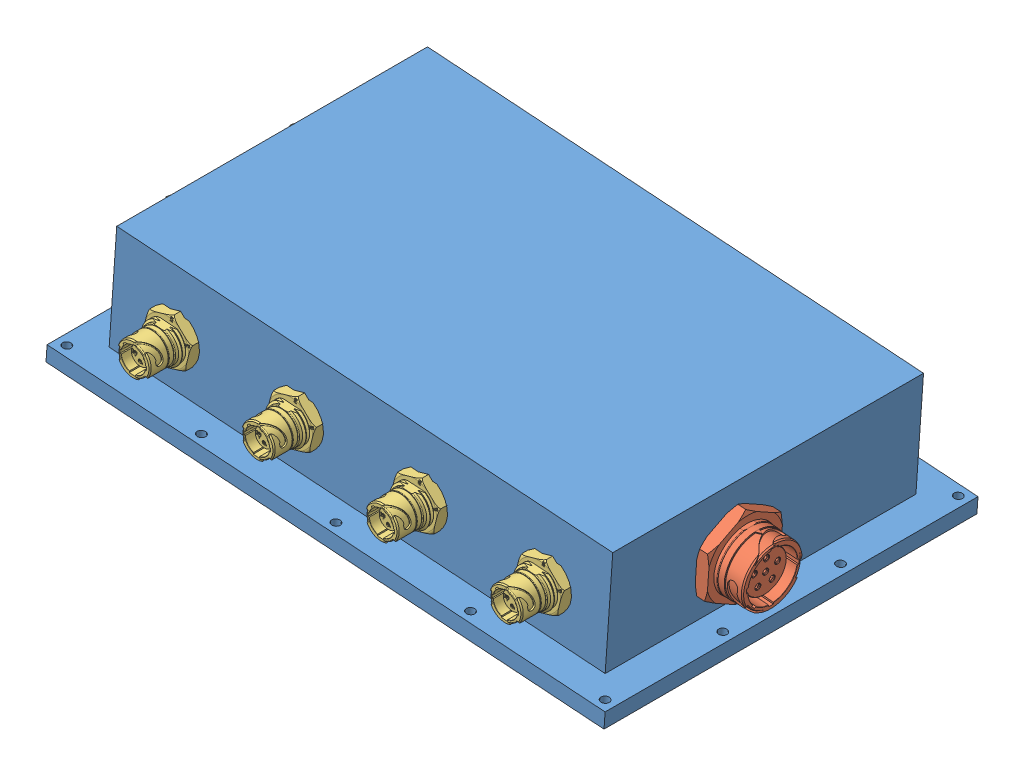
SolidWorks assembly PDB Lidless Assembly, configuration Default. Lengths in mm.
Overall size (238.42 66.62 160.89).
12 component instances, 3 part files, 33 mates.
Components (placement in the parent):
- Power Distribution Box & connector holes v1-1: Power Distribution Box & connector holes v1 [Default] at (68.8696 153.9223 199.977) x (-0.997564 0.069756 0) z (0 0 1) size (228.6 50.8 152.4)
- Samtec ACR 22-3: Samtec ACR 22 [Default] at (184.8303 120.3515 212.677) x (0 0 -1) z (0.997564 -0.069756 0) size (38.11 34.64 24.46)
- Samtec ACR-12 Plastic-2: Samtec ACR-12 Plastic [Default] at (-51.0387 136.8451 174.577) x (0 0 -1) z (-0.997564 0.069756 0) size (25.4 22 24.12)
- Samtec ACR-12 Plastic-13: Samtec ACR-12 Plastic [Default] at (92.436 126.8123 280.302) x (-0.997564 0.069756 0) z (0 0 1) size (25.4 22 24.12)
- Samtec ACR-12 Plastic-14: Samtec ACR-12 Plastic [Default] at (143.1122 123.2687 119.652) x (0.997564 -0.069756 0) z (0 0 -1) size (25.4 22 24.12)
- Samtec ACR-12 Plastic-15: Samtec ACR-12 Plastic [Default] at (143.1122 123.2687 280.302) x (-0.997564 0.069756 0) z (0 0 1) size (25.4 22 24.12)
- Samtec ACR-12 Plastic-16: Samtec ACR-12 Plastic [Default] at (41.7597 130.356 280.302) x (-0.997564 0.069756 0) z (0 0 1) size (25.4 22 24.12)
- Samtec ACR-12 Plastic-17: Samtec ACR-12 Plastic [Default] at (-8.9166 133.8996 280.302) x (-0.997564 0.069756 0) z (0 0 1) size (25.4 22 24.12)
- Samtec ACR-12 Plastic-18: Samtec ACR-12 Plastic [Default] at (-51.0387 136.8451 225.377) x (0 0 -1) z (-0.997564 0.069756 0) size (25.4 22 24.12)
- Samtec ACR-12 Plastic-19: Samtec ACR-12 Plastic [Default] at (92.436 126.8123 119.652) x (0.997564 -0.069756 0) z (0 0 -1) size (25.4 22 24.12)
- Samtec ACR-12 Plastic-20: Samtec ACR-12 Plastic [Default] at (41.7597 130.356 119.652) x (0.997564 -0.069756 0) z (0 0 -1) size (25.4 22 24.12)
- Samtec ACR-12 Plastic-21: Samtec ACR-12 Plastic [Default] at (-8.9166 133.8996 119.652) x (0.997564 -0.069756 0) z (0 0 -1) size (25.4 22 24.12)
Mates (geometry in assembly coordinates):
- Coincident50: coincident anti-aligned: plane of Power Distribution Box & connector holes v1-1 through (166.6785 96.1588 263.477) normal (0.997564 -0.069756 0); plane of Samtec ACR 22-3 through (168.4503 121.4969 212.677) normal (-0.997564 0.069756 0)
- Concentric32: concentric anti-aligned: circle of Power Distribution Box & connector holes v1-1; cylinder of Samtec ACR 22-3 through (184.8303 120.3515 212.677) axis (-0.997564 0.069756 0) radius 12.25
- Parallel30: parallel: line of Power Distribution Box & connector holes v1-1 through (167.1215 102.4933 136.477) axis (0.069756 0.997564 0); plane of Samtec ACR 22-3 through (167.8462 112.8577 197.677) normal (0 0 -1)
- Concentric35: concentric anti-aligned: cylinder of Power Distribution Box & connector holes v1-1 through (181.1204 120.6109 174.577) axis (-0.997564 0.069756 0) radius 10.2489; cylinder of Samtec ACR-12 Plastic-2 through (-51.0387 136.8451 174.577) axis (0.997564 -0.069756 0) radius 6.75
- Parallel59: parallel anti-aligned: plane of Power Distribution Box & connector holes v1-1 through (181.7299 129.3272 199.977) normal (-0.069756 -0.997564 0); plane of Samtec ACR-12 Plastic-2 through (-50.6864 143.5869 178.7295) normal (0.069756 0.997564 0)
- Tangent3: tangent: plane of Power Distribution Box & connector holes v1-1 through (-13.2101 391.1073 260.302) normal (0.997564 -0.069756 0); torus of Samtec ACR-12 Plastic-2
- Concentric36: concentric anti-aligned: cylinder of Power Distribution Box & connector holes v1-1 through (92.436 126.8123 123.777) axis (0 0 1) radius 10.2489; cylinder of Samtec ACR-12 Plastic-13 through (92.436 126.8123 280.302) axis (0 0 -1) radius 6.75
- Parallel60: parallel anti-aligned: plane of Power Distribution Box & connector holes v1-1 through (67.7073 137.3005 123.777) normal (-0.069756 -0.997564 0); plane of Samtec ACR-12 Plastic-13 through (97.0492 133.2562 280.4209) normal (0.069756 0.997564 0)
- Tangent4: tangent: plane of Power Distribution Box & connector holes v1-1 through (183.1604 377.3757 260.302) normal (0 0 -1); torus of Samtec ACR-12 Plastic-13
- Concentric37: concentric aligned: cylinder of Power Distribution Box & connector holes v1-1 through (143.1122 123.2687 123.777) axis (0 0 1) radius 10.2489; cylinder of Samtec ACR-12 Plastic-14 through (143.1122 123.2687 119.652) axis (0 0 1) radius 6.75
- Parallel61: parallel anti-aligned: plane of Power Distribution Box & connector holes v1-1 through (67.7073 137.3005 123.777) normal (-0.069756 -0.997564 0); plane of Samtec ACR-12 Plastic-14 through (139.4407 130.2919 119.5332) normal (0.069756 0.997564 0)
- Tangent5: tangent: plane of Power Distribution Box & connector holes v1-1 through (-13.2101 391.1073 139.652) normal (0 0 1); torus of Samtec ACR-12 Plastic-14
- Concentric38: concentric anti-aligned: cylinder of Power Distribution Box & connector holes v1-1 through (143.1122 123.2687 123.777) axis (0 0 1) radius 10.2489; cylinder of Samtec ACR-12 Plastic-15 through (143.1122 123.2687 280.302) axis (0 0 -1) radius 6.75
- Parallel62: parallel anti-aligned: plane of Power Distribution Box & connector holes v1-1 through (67.7073 137.3005 123.777) normal (-0.069756 -0.997564 0); plane of Samtec ACR-12 Plastic-15 through (147.7254 129.7126 280.4209) normal (0.069756 0.997564 0)
- Tangent6: tangent: plane of Power Distribution Box & connector holes v1-1 through (183.1604 377.3757 260.302) normal (0 0 -1); torus of Samtec ACR-12 Plastic-15
- Tangent7: tangent: plane of Power Distribution Box & connector holes v1-1 through (183.1604 377.3757 260.302) normal (0 0 -1); torus of Samtec ACR-12 Plastic-16
- Concentric39: concentric anti-aligned: cylinder of Power Distribution Box & connector holes v1-1 through (41.7597 130.356 123.777) axis (0 0 1) radius 10.2489; cylinder of Samtec ACR-12 Plastic-16 through (41.7597 130.356 280.302) axis (0 0 -1) radius 6.75
- Parallel63: parallel anti-aligned: plane of Power Distribution Box & connector holes v1-1 through (67.7073 137.3005 123.777) normal (-0.069756 -0.997564 0); plane of Samtec ACR-12 Plastic-16 through (46.3729 136.7999 280.4209) normal (0.069756 0.997564 0)
- Tangent8: tangent: plane of Power Distribution Box & connector holes v1-1 through (183.1604 377.3757 260.302) normal (0 0 -1); torus of Samtec ACR-12 Plastic-17
- Concentric40: concentric anti-aligned: cylinder of Power Distribution Box & connector holes v1-1 through (-8.9166 133.8996 123.777) axis (0 0 1) radius 10.2489; cylinder of Samtec ACR-12 Plastic-17 through (-8.9166 133.8996 280.302) axis (0 0 -1) radius 6.75
- Parallel64: parallel anti-aligned: plane of Power Distribution Box & connector holes v1-1 through (67.7073 137.3005 123.777) normal (-0.069756 -0.997564 0); plane of Samtec ACR-12 Plastic-17 through (-4.3033 140.3435 280.4209) normal (0.069756 0.997564 0)
- Concentric41: concentric anti-aligned: cylinder of Power Distribution Box & connector holes v1-1 through (181.1204 120.6109 225.377) axis (-0.997564 0.069756 0) radius 10.2489; cylinder of Samtec ACR-12 Plastic-18 through (-51.0387 136.8451 225.377) axis (0.997564 -0.069756 0) radius 6.75
- Parallel65: parallel anti-aligned: plane of Power Distribution Box & connector holes v1-1 through (181.7299 129.3272 199.977) normal (-0.069756 -0.997564 0); plane of Samtec ACR-12 Plastic-18 through (-50.6864 143.5869 229.5295) normal (0.069756 0.997564 0)
- Tangent9: tangent: plane of Power Distribution Box & connector holes v1-1 through (-13.2101 391.1073 260.302) normal (0.997564 -0.069756 0); torus of Samtec ACR-12 Plastic-18
- Concentric42: concentric aligned: cylinder of Power Distribution Box & connector holes v1-1 through (92.436 126.8123 123.777) axis (0 0 1) radius 10.2489; cylinder of Samtec ACR-12 Plastic-19 through (92.436 126.8123 119.652) axis (0 0 1) radius 6.75
- Parallel66: parallel anti-aligned: plane of Power Distribution Box & connector holes v1-1 through (67.7073 137.3005 123.777) normal (-0.069756 -0.997564 0); plane of Samtec ACR-12 Plastic-19 through (88.7644 133.8356 119.5332) normal (0.069756 0.997564 0)
- Tangent10: tangent: plane of Power Distribution Box & connector holes v1-1 through (-13.2101 391.1073 139.652) normal (0 0 1); torus of Samtec ACR-12 Plastic-19
- Tangent11: tangent: plane of Power Distribution Box & connector holes v1-1 through (-13.2101 391.1073 139.652) normal (0 0 1); torus of Samtec ACR-12 Plastic-20
- Concentric43: concentric aligned: cylinder of Power Distribution Box & connector holes v1-1 through (41.7597 130.356 123.777) axis (0 0 1) radius 10.2489; cylinder of Samtec ACR-12 Plastic-20 through (41.7597 130.356 119.652) axis (0 0 1) radius 6.75
- Parallel67: parallel anti-aligned: plane of Power Distribution Box & connector holes v1-1 through (67.7073 137.3005 123.777) normal (-0.069756 -0.997564 0); plane of Samtec ACR-12 Plastic-20 through (38.0882 137.3792 119.5332) normal (0.069756 0.997564 0)
- Tangent12: tangent: plane of Power Distribution Box & connector holes v1-1 through (-13.2101 391.1073 139.652) normal (0 0 1); torus of Samtec ACR-12 Plastic-21
- Concentric44: concentric aligned: cylinder of Power Distribution Box & connector holes v1-1 through (-8.9166 133.8996 123.777) axis (0 0 1) radius 10.2489; cylinder of Samtec ACR-12 Plastic-21 through (-8.9166 133.8996 119.652) axis (0 0 1) radius 6.75
- Parallel68: parallel anti-aligned: plane of Power Distribution Box & connector holes v1-1 through (67.7073 137.3005 123.777) normal (-0.069756 -0.997564 0); plane of Samtec ACR-12 Plastic-21 through (-12.5881 140.9228 119.5332) normal (0.069756 0.997564 0)
